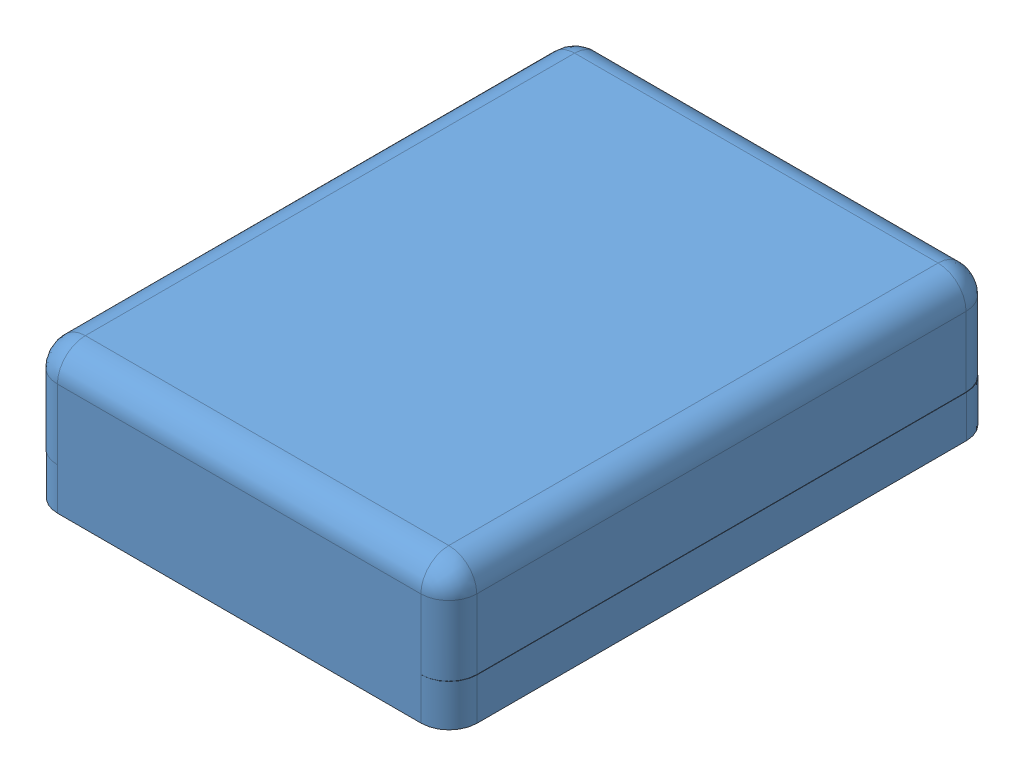
SolidWorks assembly TestingCasing, configuration Default. Lengths in mm.
Overall size (76.26 25.53 99.06).
6 component instances, 3 part files, 12 mates.
Components (placement in the parent):
- IMU+MicroTop-1: IMU+MicroTop [Default] at (5.5101 38.9646 26.3245) x (1 0 0) z (0 0 -1) size (76.26 25.4 99.06)
- IMU+MicroBottom-1: IMU+MicroBottom [Default] at (12.9858 42.0126 108.9133) size (63.5 10.79 86.36)
- spacer-1: spacer [Default] at (66.3258 42.0126 32.7133) size (10.16 9.65 10.16)
- spacer-2: spacer [Default] at (66.3258 42.0126 108.9133) size (10.16 9.65 10.16)
- spacer-3: spacer [Default] at (12.9858 42.0126 32.7133) size (10.16 9.65 10.16)
- spacer-4: spacer [Default] at (12.9858 42.0126 108.9133) size (10.16 9.65 10.16)
Mates (geometry in assembly coordinates):
- Parallel1: parallel: plane of IMU+MicroTop-1 through (5.5101 51.6646 26.3245) normal (0 0 1); plane of IMU+MicroBottom-1 through (12.9858 36.2976 27.6333) normal (0 0 -1)
- Parallel2: parallel: plane of IMU+MicroTop-1 through (71.5501 51.6646 26.3245) normal (-1 0 0); plane of IMU+MicroBottom-1 through (71.4058 36.2976 108.9133) normal (1 0 0)
- Parallel3: parallel: plane of IMU+MicroTop-1 through (5.5101 51.6646 26.3245) normal (0 -1 0); plane of IMU+MicroBottom-1 through (12.9858 42.0126 108.9133) normal (0 1 0)
- Coincident7: coincident: plane of IMU+MicroBottom-1 through (12.9858 42.0126 108.9133) normal (0 1 0); plane of spacer-2 through (66.3258 42.0126 108.9133) normal (0 -1 0)
- Coincident8: coincident: circle of IMU+MicroBottom-1; circle of spacer-2
- Coincident9: coincident: plane of IMU+MicroBottom-1 through (12.9858 42.0126 108.9133) normal (0 1 0); plane of spacer-3 through (12.9858 42.0126 32.7133) normal (0 -1 0)
- Coincident10: coincident: circle of IMU+MicroBottom-1; circle of spacer-3
- Coincident11: coincident: plane of IMU+MicroBottom-1 through (12.9858 42.0126 108.9133) normal (0 1 0); plane of spacer-1 through (66.3258 42.0126 32.7133) normal (0 -1 0)
- Coincident12: coincident: circle of IMU+MicroBottom-1; circle of spacer-1
- Coincident13: coincident: plane of IMU+MicroBottom-1 through (12.9858 42.0126 108.9133) normal (0 1 0); plane of spacer-4 through (12.9858 42.0126 108.9133) normal (0 -1 0)
- Coincident14: coincident: circle of IMU+MicroBottom-1; circle of spacer-4
- Coincident15: coincident: plane of IMU+MicroTop-1 through (5.5101 51.6646 26.3245) normal (0 -1 0); plane of spacer-3 through (12.9858 51.6646 32.7133) normal (0 1 0)
